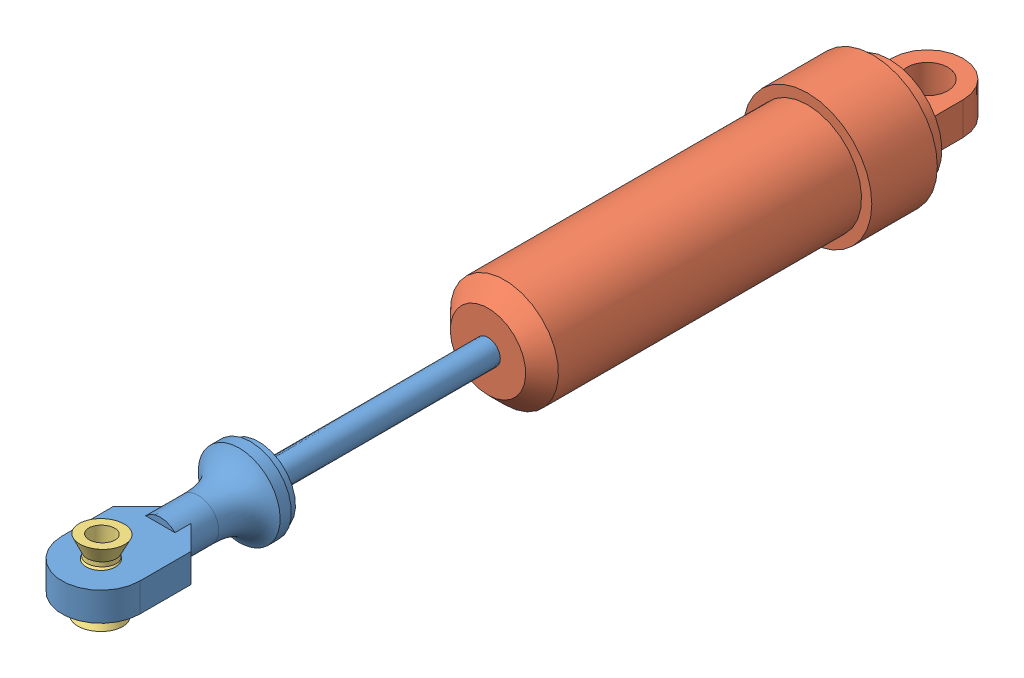
SolidWorks assembly Suspension_Rear, configuration Default. Lengths in mm.
Overall size (15.7 15.7 110).
3 component instances, 3 part files, 4 mates.
Components (placement in the parent):
- Suspension Inner_Rear-1: Suspension Inner_Rear [Default] at (14.4288 30.3657 20.0829) size (10 10 59)
- Suspension Outer_Rear-1: Suspension Outer_Rear [Default] at (14.4288 30.3657 27.0829) x (0 -1 0) z (0 0 -1) size (15.7 15.7 58)
- Turnbuckle Ball Spacer-1: Turnbuckle Ball Spacer [Default] at (14.4288 30.3657 74.3329) x (-0.040986 0.99667 -0.07049) z (-0.169655 0.062583 0.983514) size (8.25 5.2 5.2)
Mates (geometry in assembly coordinates):
- Concentric1: concentric: sphere of Suspension Inner_Rear-1; sphere of Turnbuckle Ball Spacer-1
- Concentric2: concentric: cylinder of Suspension Inner_Rear-1 through (14.4288 30.3657 55.0829) axis (0 0 -1) radius 1.5; cylinder of Suspension Outer_Rear-1 through (14.4288 30.3657 -7.9171) axis (0 0 1) radius 1.5
- LimitDistance1: limit distance = 28 mm: plane of Suspension Inner_Rear-1 through (14.4288 30.3657 55.0829) normal (0 0 -1); plane of Suspension Outer_Rear-1 through (14.4288 30.3657 27.0829) normal (0 0 1)
- Parallel1: parallel: plane of Suspension Inner_Rear-1 through (14.4288 28.6157 74.3329) normal (0 -1 0); plane of Suspension Outer_Rear-1 through (14.4288 28.3657 -26.5421) normal (0 -1 0)
